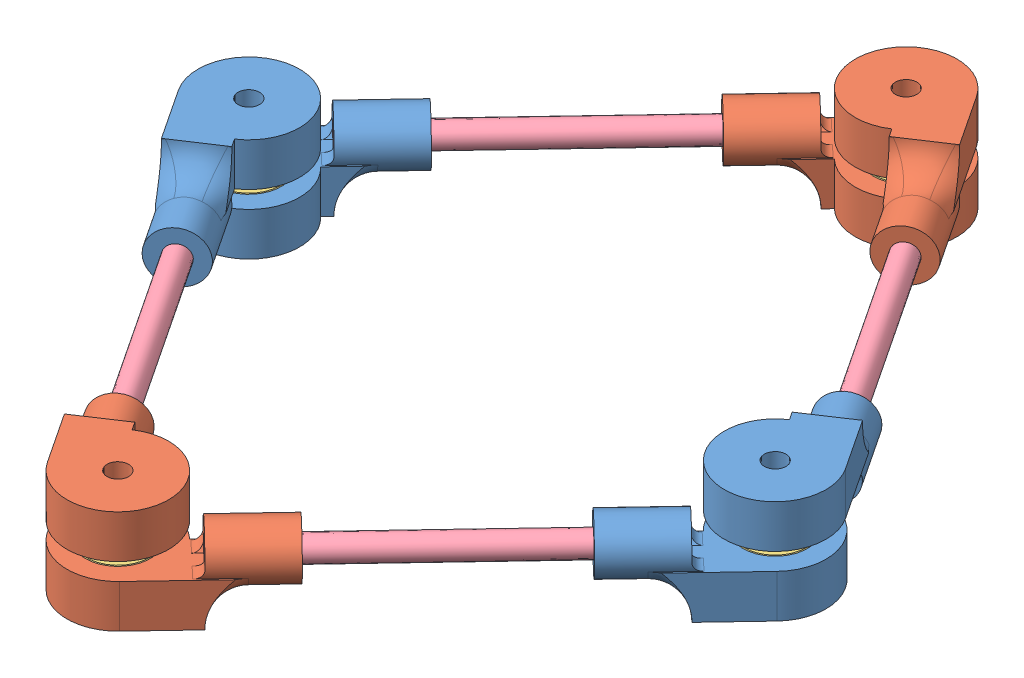
SolidWorks assembly Assem1, configuration Default. Lengths in mm.
Overall size (106.55 15.24 128.44).
20 component instances, 4 part files, 46 mates.
Components (placement in the parent):
- leftjoint-1: leftjoint [Default] at (20.3505 11.5506 172.9117) x (-0.833793 0 0.552078) z (-0.552078 0 -0.833793) size (15.21 11.37 26.54)
- rightjoint-1: rightjoint [Default] at (-16.2119 11.5506 228.2889) x (0.725731 0 0.687979) z (0.687979 0 -0.725731) size (15.21 11.37 26.54)
- leftjoint-2: leftjoint [Default] at (18.7375 11.5506 191.4218) x (-0.725731 0 -0.687979) z (-0.687979 0 0.725731) size (15.21 11.37 26.54)
- 60355K501_BALL BEARING-1: 60355K501_BALL BEARING [60355K501] at (22.1346 8.2963 182.3925) x (-0.837169 0 -0.546944) z (0 -1 0) size (9.53 9.53 3.97)
- 60355K501_BALL BEARING-2: 60355K501_BALL BEARING [60355K501] at (22.1346 14.805 182.3925) x (1 0 0) z (0 1 0) size (9.53 9.53 3.97)
- rightjoint-2: rightjoint [Default] at (-33.0787 11.5506 226.8191) x (-0.833793 0 0.552078) z (-0.552078 0 -0.833793) size (15.21 11.37 26.54)
- 60355K501_BALL BEARING-3: 60355K501_BALL BEARING [60355K501] at (-25.047 8.2963 232.1631) x (1 0 0) z (0 1 0) size (9.53 9.53 3.97)
- 60355K501_BALL BEARING-4: 60355K501_BALL BEARING [60355K501] at (-25.047 14.805 232.1631) x (-0.837169 0 -0.546944) z (0 -1 0) size (9.53 9.53 3.97)
- bar-1: bar [Default] at (-16.2119 11.5506 228.2889) x (-0.386303 0.846559 -0.366208) z (0.687979 0 -0.725731) size (3.43 3.43 50.8)
- leftjoint-3: leftjoint [Default] at (-59.5113 11.5506 165.9524) x (0.725731 0 0.687979) z (0.687979 0 -0.725731) size (15.21 11.37 26.54)
- leftjoint-4: leftjoint [Default] at (-61.1243 11.5506 184.4624) x (0.833793 0 -0.552078) z (0.552078 0 0.833793) size (15.21 11.37 26.54)
- 60355K501_BALL BEARING-5: 60355K501_BALL BEARING [60355K501] at (-62.9085 8.2963 174.9816) x (1 0 0) z (0 1 0) size (9.53 9.53 3.97)
- 60355K501_BALL BEARING-6: 60355K501_BALL BEARING [60355K501] at (-62.9085 14.805 174.9816) x (-0.837169 0 -0.546944) z (0 -1 0) size (9.53 9.53 3.97)
- bar-2: bar [Default] at (-33.0787 11.5506 226.8191) x (0.63149 -0.652986 -0.418127) z (-0.552078 0 -0.833793) size (3.43 3.43 50.8)
- rightjoint-5: rightjoint [Default] at (-24.5619 11.5506 129.0852) x (-0.725731 0 -0.687979) z (-0.687979 0 0.725731) size (15.21 11.37 26.54)
- rightjoint-6: rightjoint [Default] at (-7.6951 11.5506 130.5551) x (0.833793 0 -0.552078) z (0.552078 0 0.833793) size (15.21 11.37 26.54)
- 60355K501_BALL BEARING-7: 60355K501_BALL BEARING [60355K501] at (-15.7269 14.805 125.211) x (1 0 0) z (0 1 0) size (9.53 9.53 3.97)
- 60355K501_BALL BEARING-8: 60355K501_BALL BEARING [60355K501] at (-15.7269 8.2963 125.211) x (-0.837169 0 -0.546944) z (0 -1 0) size (9.53 9.53 3.97)
- bar-3: bar [Default] at (-59.5113 11.5506 165.9524) x (-0.108733 0.988712 -0.103077) z (0.687979 0 -0.725731) size (3.43 3.43 50.8)
- bar-4: bar [Default] at (20.3505 11.5506 172.9117) x (0.63149 -0.652986 -0.418127) z (-0.552078 0 -0.833793) size (3.43 3.43 50.8)
Mates (geometry in assembly coordinates):
- Concentric2: concentric anti-aligned: cylinder of leftjoint-2 through (22.1346 6.3119 182.3925) axis (0 1 0) radius 4.7625; cylinder of 60355K501_BALL BEARING-1 through (22.1346 6.3119 182.3925) axis (0 -1 0) radius 4.7625
- Coincident2: coincident aligned: plane of leftjoint-2 through (18.7375 10.2806 191.4218) normal (0 1 0); plane of 60355K501_BALL BEARING-1 through (24.6309 10.2806 178.5716) normal (0 1 0)
- Coincident3: coincident aligned: plane of leftjoint-1 through (20.3505 12.8206 172.9117) normal (0 -1 0); plane of 60355K501_BALL BEARING-2 through (22.1346 12.8206 177.8285) normal (0 -1 0)
- Concentric3: concentric anti-aligned: cylinder of leftjoint-1 through (22.1346 16.7894 182.3925) axis (0 -1 0) radius 4.7625; cylinder of 60355K501_BALL BEARING-2 through (22.1346 16.7894 182.3925) axis (0 1 0) radius 4.7625
- Concentric4: concentric anti-aligned: cylinder of 60355K501_BALL BEARING-1 through (22.1346 6.3119 182.3925) axis (0 -1 0) radius 1.5875; cylinder of 60355K501_BALL BEARING-2 through (22.1346 16.7894 182.3925) axis (0 1 0) radius 1.5875
- Concentric5: concentric aligned: cylinder of rightjoint-1 through (-25.047 6.3119 232.1631) axis (0 1 0) radius 4.7625; cylinder of 60355K501_BALL BEARING-3 through (-25.047 10.2806 232.1631) axis (0 1 0) radius 4.7625
- Coincident6: coincident aligned: plane of rightjoint-1 through (-16.2119 10.2806 228.2889) normal (0 1 0); plane of 60355K501_BALL BEARING-3 through (-25.047 10.2806 227.5991) normal (0 1 0)
- Concentric6: concentric aligned: cylinder of rightjoint-2 through (-25.047 16.7894 232.1631) axis (0 -1 0) radius 4.7625; cylinder of 60355K501_BALL BEARING-4 through (-25.047 12.8206 232.1631) axis (0 -1 0) radius 4.7625
- Coincident8: coincident aligned: plane of rightjoint-2 through (-33.0787 12.8206 226.8191) normal (0 -1 0); plane of 60355K501_BALL BEARING-4 through (-23.444 12.8206 229.7096) normal (0 -1 0)
- Concentric7: concentric anti-aligned: cylinder of 60355K501_BALL BEARING-3 through (-25.047 10.2806 232.1631) axis (0 1 0) radius 1.5875; cylinder of 60355K501_BALL BEARING-4 through (-25.047 12.8206 232.1631) axis (0 -1 0) radius 1.5875
- Concentric8: concentric anti-aligned: cylinder of leftjoint-2 through (11.7476 11.5506 198.7952) axis (0.687979 0 -0.725731) radius 1.7145; cylinder of bar-1 through (18.7375 11.5506 191.4218) axis (-0.687979 0 0.725731) radius 1.7145
- Coincident11: coincident anti-aligned: plane of leftjoint-2 through (18.7375 3.9306 191.4218) normal (-0.687979 0 0.725731); plane of bar-1 through (18.7375 11.5506 191.4218) normal (0.687979 0 -0.725731)
- Lock1: lock: unknown of leftjoint-2; unknown of bar-1
- Concentric12: concentric aligned: cylinder of rightjoint-1 through (-9.222 11.5506 220.9155) axis (-0.687979 0 0.725731) radius 1.7145; cylinder of bar-1 through (18.7375 11.5506 191.4218) axis (-0.687979 0 0.725731) radius 1.7145
- Coincident12: coincident anti-aligned: plane of rightjoint-1 through (-16.2119 3.9306 228.2889) normal (0.687979 0 -0.725731); plane of bar-1 through (-16.2119 11.5506 228.2889) normal (-0.687979 0 0.725731)
- Lock2: lock: unknown of rightjoint-1; unknown of bar-1
- Concentric14: concentric aligned: cylinder of leftjoint-3 through (-62.9085 6.3119 174.9816) axis (0 1 0) radius 4.7625; cylinder of 60355K501_BALL BEARING-5 through (-62.9085 10.2806 174.9816) axis (0 1 0) radius 4.7625
- Coincident14: coincident aligned: plane of leftjoint-3 through (-59.5113 10.2806 165.9524) normal (0 1 0); plane of 60355K501_BALL BEARING-5 through (-62.9085 10.2806 170.4176) normal (0 1 0)
- Concentric15: concentric aligned: cylinder of leftjoint-4 through (-62.9085 16.7894 174.9816) axis (0 -1 0) radius 4.7625; cylinder of 60355K501_BALL BEARING-6 through (-62.9085 12.8206 174.9816) axis (0 -1 0) radius 4.7625
- Coincident15: coincident aligned: plane of leftjoint-4 through (-61.1243 12.8206 184.4624) normal (0 -1 0); plane of 60355K501_BALL BEARING-6 through (-60.4122 12.8206 171.1607) normal (0 -1 0)
- Concentric16: concentric anti-aligned: cylinder of 60355K501_BALL BEARING-5 through (-62.9085 10.2806 174.9816) axis (0 1 0) radius 1.5875; cylinder of 60355K501_BALL BEARING-6 through (-62.9085 12.8206 174.9816) axis (0 -1 0) radius 1.5875
- Concentric18: concentric aligned: cylinder of rightjoint-2 through (-38.6878 11.5506 218.3477) axis (0.552078 0 0.833793) radius 1.7145; cylinder of bar-2 through (-61.1243 11.5506 184.4624) axis (0.552078 0 0.833793) radius 1.7145
- Coincident17: coincident anti-aligned: plane of rightjoint-2 through (-33.0787 19.1706 226.8191) normal (-0.552078 0 -0.833793); plane of bar-2 through (-33.0787 11.5506 226.8191) normal (0.552078 0 0.833793)
- Lock3: lock: unknown of rightjoint-2; unknown of bar-2
- Concentric23: concentric anti-aligned: cylinder of leftjoint-4 through (-55.5152 11.5506 192.9337) axis (-0.552078 0 -0.833793) radius 1.7145; cylinder of bar-2 through (-61.1243 11.5506 184.4624) axis (0.552078 0 0.833793) radius 1.7145
- Coincident19: coincident anti-aligned: plane of leftjoint-4 through (-61.1243 19.1706 184.4624) normal (0.552078 0 0.833793); plane of bar-2 through (-61.1243 11.5506 184.4624) normal (-0.552078 0 -0.833793)
- Lock4: lock: unknown of leftjoint-4; unknown of bar-2
- Concentric25: concentric anti-aligned: cylinder of rightjoint-6 through (-15.7269 16.7894 125.211) axis (0 -1 0) radius 4.7625; cylinder of 60355K501_BALL BEARING-7 through (-15.7269 16.7894 125.211) axis (0 1 0) radius 4.7625
- Coincident21: coincident aligned: plane of rightjoint-6 through (-7.6951 12.8206 130.5551) normal (0 -1 0); plane of 60355K501_BALL BEARING-7 through (-15.7269 12.8206 120.647) normal (0 -1 0)
- Concentric26: concentric anti-aligned: cylinder of rightjoint-5 through (-15.7269 6.3119 125.211) axis (0 1 0) radius 4.7625; cylinder of 60355K501_BALL BEARING-8 through (-15.7269 6.3119 125.211) axis (0 -1 0) radius 4.7625
- Coincident22: coincident aligned: plane of rightjoint-5 through (-24.5619 10.2806 129.0852) normal (0 1 0); plane of 60355K501_BALL BEARING-8 through (-13.2306 10.2806 121.3901) normal (0 1 0)
- Concentric27: concentric anti-aligned: cylinder of 60355K501_BALL BEARING-7 through (-15.7269 16.7894 125.211) axis (0 1 0) radius 1.5875; cylinder of 60355K501_BALL BEARING-8 through (-15.7269 6.3119 125.211) axis (0 -1 0) radius 1.5875
- Concentric28: concentric aligned: cylinder of leftjoint-3 through (-52.5214 11.5506 158.5789) axis (-0.687979 0 0.725731) radius 1.7145; cylinder of bar-3 through (-24.5619 11.5506 129.0852) axis (-0.687979 0 0.725731) radius 1.7145
- Coincident24: coincident anti-aligned: plane of leftjoint-3 through (-59.5113 3.9306 165.9524) normal (0.687979 0 -0.725731); plane of bar-3 through (-59.5113 11.5506 165.9524) normal (-0.687979 0 0.725731)
- Lock5: lock: unknown of leftjoint-3; unknown of bar-3
- Concentric30: concentric anti-aligned: cylinder of rightjoint-5 through (-31.5518 11.5506 136.4587) axis (0.687979 0 -0.725731) radius 1.7145; cylinder of bar-3 through (-24.5619 11.5506 129.0852) axis (-0.687979 0 0.725731) radius 1.7145
- Coincident25: coincident anti-aligned: plane of rightjoint-5 through (-24.5619 3.9306 129.0852) normal (-0.687979 0 0.725731); plane of bar-3 through (-24.5619 11.5506 129.0852) normal (0.687979 0 -0.725731)
- Concentric32: concentric anti-aligned: cylinder of rightjoint-6 through (-2.086 11.5506 139.0264) axis (-0.552078 0 -0.833793) radius 1.7145; cylinder of bar-4 through (-7.6951 11.5506 130.5551) axis (0.552078 0 0.833793) radius 1.7145
- Coincident26: coincident anti-aligned: plane of rightjoint-6 through (-7.6951 19.1706 130.5551) normal (0.552078 0 0.833793); plane of bar-4 through (-7.6951 11.5506 130.5551) normal (-0.552078 0 -0.833793)
- Lock7: lock: unknown of rightjoint-6; unknown of bar-4
- Concentric43: concentric aligned: cylinder of leftjoint-1 through (14.7414 11.5506 164.4404) axis (0.552078 0 0.833793) radius 1.7145; cylinder of bar-4 through (-7.6951 11.5506 130.5551) axis (0.552078 0 0.833793) radius 1.7145
- Coincident29: coincident anti-aligned: plane of leftjoint-1 through (20.3505 19.1706 172.9117) normal (-0.552078 0 -0.833793); plane of bar-4 through (20.3505 11.5506 172.9117) normal (0.552078 0 0.833793)
- Lock8: lock: unknown of leftjoint-1; unknown of bar-4
- Distance10: distance = 2.54 mm anti-aligned: plane of leftjoint-3 through (-59.5113 10.2806 165.9524) normal (0 1 0); plane of leftjoint-4 through (-61.1243 12.8206 184.4624) normal (0 -1 0)
- Distance11: distance = 2.54 mm anti-aligned: plane of rightjoint-5 through (-24.5619 10.2806 129.0852) normal (0 1 0); plane of rightjoint-6 through (-7.6951 12.8206 130.5551) normal (0 -1 0)
- Distance12: distance = 2.54 mm anti-aligned: plane of leftjoint-2 through (18.7375 10.2806 191.4218) normal (0 1 0); plane of leftjoint-1 through (20.3505 12.8206 172.9117) normal (0 -1 0)
